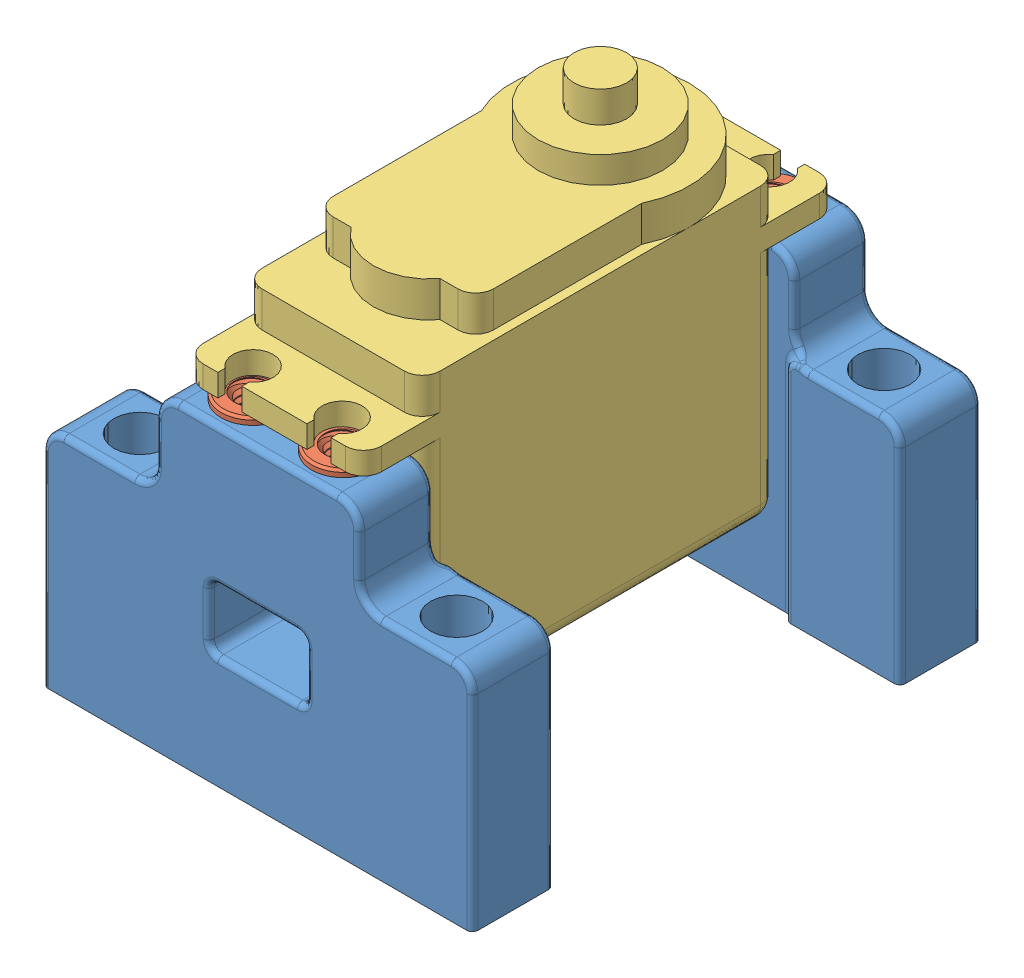
SolidWorks assembly MS-A-0013e-Arm Servo Mount Assembly, configuration Default. Lengths in mm.
Overall size (48.26 52.81 57.28).
11 component instances, 3 part files, 27 mates.
Components (placement in the parent):
- MS-P-0056-Shoulder Servo Mount-6: MS-P-0056-Shoulder Servo Mount [Default] at (-47.9263 -13.6934 17.7337) x (-1 0 0) z (0 1 0) size (48.26 9.14 35.05)
- MS-P-0056-Shoulder Servo Mount-7: MS-P-0056-Shoulder Servo Mount [Default] at (-47.9263 -13.6934 -30.2663) x (1 0 0) z (0 1 0) size (48.26 9.14 35.05)
- 97171A170_ HEAT-SET INSERT FOR PLASTIC-1: 97171A170_ HEAT-SET INSERT FOR PLASTIC [97171A170] at (-65.7063 -7.191 17.7337) x (0.915319 0 -0.402729) z (-0.402729 0 -0.915319) size (7.14 9.57 7.14)
- 97171A170_ HEAT-SET INSERT FOR PLASTIC-2: 97171A170_ HEAT-SET INSERT FOR PLASTIC [97171A170] at (-30.1463 -7.191 17.7337) x (1 0 0) z (0 0 -1) size (7.14 9.57 7.14)
- 97171A170_ HEAT-SET INSERT FOR PLASTIC-4: 97171A170_ HEAT-SET INSERT FOR PLASTIC [97171A170] at (-30.1463 -7.191 -30.2663) x (-1 0 0) z (0 0 1) size (7.14 9.57 7.14)
- 97171A170_ HEAT-SET INSERT FOR PLASTIC-6: 97171A170_ HEAT-SET INSERT FOR PLASTIC [97171A170] at (-65.7063 -7.191 -30.2663) x (1 0 0) z (0 0 -1) size (7.14 9.57 7.14)
- 97171A170_ HEAT-SET INSERT FOR PLASTIC-7: 97171A170_ HEAT-SET INSERT FOR PLASTIC [97171A170] at (-42.8463 8.1252 -30.2663) x (0.999861 0 -0.016687) z (0.016687 0 0.999861) size (7.14 9.57 7.14)
- 97171A170_ HEAT-SET INSERT FOR PLASTIC-8: 97171A170_ HEAT-SET INSERT FOR PLASTIC [97171A170] at (-53.0063 8.1252 -30.2663) size (7.14 9.57 7.14)
- 97171A170_ HEAT-SET INSERT FOR PLASTIC-9: 97171A170_ HEAT-SET INSERT FOR PLASTIC [97171A170] at (-42.8463 8.1252 17.7337) size (7.14 9.57 7.14)
- 97171A170_ HEAT-SET INSERT FOR PLASTIC-10: 97171A170_ HEAT-SET INSERT FOR PLASTIC [97171A170] at (-53.0063 8.1252 17.7337) size (7.14 9.57 7.14)
- MS-C-0032-Gripper Shoulder Servo-1: MS-C-0032-Gripper Shoulder Servo [Default] at (-48.0063 17.0406 -6.2663) x (0 0 -1) z (1 0 0) size (53.2 43.5 20)
Mates (geometry in assembly coordinates):
- Concentric18: concentric anti-aligned: circle of MS-P-0048 - Servo Mount Piece-6; circle of 97171A170_ HEAT-SET INSERT FOR PLASTIC-1
- Concentric22: concentric anti-aligned: circle of 11886-2/11886_upper-1; circle of MS-P-0048 - Servo Mount Piece-7
- Coincident23: coincident anti-aligned: plane of MS-P-0048 - Servo Mount Piece-6 through (-65.7063 -15.3444 17.7337) normal (0 -1 0); plane of 97171A170_ HEAT-SET INSERT FOR PLASTIC-1 through (-63.4861 -15.3444 16.7568) normal (0 1 0)
- Concentric23: concentric anti-aligned: circle of MS-P-0048 - Servo Mount Piece-6; circle of 97171A170_ HEAT-SET INSERT FOR PLASTIC-2
- Coincident28: coincident anti-aligned: plane of MS-P-0048 - Servo Mount Piece-6 through (-30.1463 -15.3444 17.7337) normal (0 -1 0); plane of 97171A170_ HEAT-SET INSERT FOR PLASTIC-2 through (-27.7206 -15.3444 17.7337) normal (0 1 0)
- Concentric24: concentric aligned: circle of MS-P-0048 - Servo Mount Piece-7; circle of 97171A170_ HEAT-SET INSERT FOR PLASTIC-4
- Coincident29: coincident anti-aligned: plane of MS-P-0048 - Servo Mount Piece-7 through (-30.1463 -15.3444 -30.2663) normal (0 -1 0); plane of 97171A170_ HEAT-SET INSERT FOR PLASTIC-4 through (-32.572 -15.3444 -30.2663) normal (0 1 0)
- Concentric25: concentric anti-aligned: circle of MS-P-0048 - Servo Mount Piece-7; circle of 97171A170_ HEAT-SET INSERT FOR PLASTIC-6
- Coincident30: coincident anti-aligned: plane of MS-P-0048 - Servo Mount Piece-7 through (-65.7063 -15.3444 -30.2663) normal (0 -1 0); plane of 97171A170_ HEAT-SET INSERT FOR PLASTIC-6 through (-63.2806 -15.3444 -30.2663) normal (0 1 0)
- Coincident38: coincident anti-aligned: line of MS-P-0048 - Servo Mount Piece-7 through (-42.8463 14.2466 -30.2663) axis (0 1 0); line of 97171A170_ HEAT-SET INSERT FOR PLASTIC-7 through (-42.8463 17.8175 -30.2663) axis (0 -1 0)
- Coincident39: coincident anti-aligned: plane of MS-P-0048 - Servo Mount Piece-7 through (-47.9263 16.2786 -30.2663) normal (0 1 0); plane of 97171A170_ HEAT-SET INSERT FOR PLASTIC-7 through (-40.421 16.2786 -30.3068) normal (0 -1 0)
- Coincident40: coincident anti-aligned: line of MS-P-0048 - Servo Mount Piece-7 through (-53.0063 14.2466 -30.2663) axis (0 1 0); line of 97171A170_ HEAT-SET INSERT FOR PLASTIC-8 through (-53.0063 17.8175 -30.2663) axis (0 -1 0)
- Coincident41: coincident anti-aligned: plane of MS-P-0048 - Servo Mount Piece-7 through (-47.9263 16.2786 -30.2663) normal (0 1 0); plane of 97171A170_ HEAT-SET INSERT FOR PLASTIC-8 through (-50.5806 16.2786 -30.2663) normal (0 -1 0)
- Coincident42: coincident anti-aligned: line of MS-P-0048 - Servo Mount Piece-6 through (-42.8463 14.2466 17.7337) axis (0 1 0); line of 97171A170_ HEAT-SET INSERT FOR PLASTIC-9 through (-42.8463 17.8175 17.7337) axis (0 -1 0)
- Coincident43: coincident anti-aligned: plane of MS-P-0048 - Servo Mount Piece-6 through (-47.9263 16.2786 17.7337) normal (0 1 0); plane of 97171A170_ HEAT-SET INSERT FOR PLASTIC-9 through (-40.4206 16.2786 17.7337) normal (0 -1 0)
- Coincident44: coincident anti-aligned: line of MS-P-0048 - Servo Mount Piece-6 through (-53.0063 14.2466 17.7337) axis (0 1 0); line of 97171A170_ HEAT-SET INSERT FOR PLASTIC-10 through (-53.0063 17.8175 17.7337) axis (0 -1 0)
- Coincident46: coincident anti-aligned: plane of 11886-2/11886_upper-1 through (-24.7983 61.0137 -1.8155) normal (0 -1 0); plane of 97171A170_ HEAT-SET INSERT FOR PLASTIC-9 through (-39.2776 17.0406 17.7337) normal (0 1 0)
- Concentric26: concentric aligned: cylinder of 11886-2/11886_upper-1 through (-9.2983 69.7137 -6.4155) axis (0 -1 0) radius 2.25; cylinder of 97171A170_ HEAT-SET INSERT FOR PLASTIC-9 through (-42.8463 8.1252 17.7337) axis (0 -1 0) radius 3.5687
- Coincident47: coincident anti-aligned: plane of 11886-2/11886_upper-1 through (-24.7983 61.0137 -1.8155) normal (0 -1 0); plane of 97171A170_ HEAT-SET INSERT FOR PLASTIC-7 through (-39.2781 17.0406 -30.3259) normal (0 1 0)
- Parallel2: parallel aligned: plane of 11886-2/11886_upper-1 through (-3.7983 69.7137 39.6845) normal (0 0 1); plane of MS-P-0048 - Servo Mount Piece-7 through (-72.0563 -18.7734 -25.6943) normal (0 0 1)
- Parallel3: parallel aligned: plane of 11886-2/11886_upper-1 through (-3.7983 69.7137 -1.8155) normal (0 0 -1); plane of MS-P-0048 - Servo Mount Piece-6 through (-23.7963 -18.7734 13.1617) normal (0 0 -1)
- Coincident57: coincident anti-aligned: plane of MS-P-0048 - Servo Mount Piece-6 through (-47.9263 16.2786 17.7337) normal (0 1 0); plane of 97171A170_ HEAT-SET INSERT FOR PLASTIC-10 through (-50.5806 16.2786 17.7337) normal (0 -1 0)
- Coincident58: coincident aligned: plane of MS-P-0048 - Servo Mount Piece-6 through (-72.0563 -18.7734 22.3057) normal (-1 0 0); plane of MS-P-0048 - Servo Mount Piece-7 through (-72.0563 -18.7734 -34.8383) normal (-1 0 0)
- Coincident59: coincident aligned: plane of MS-P-0048 - Servo Mount Piece-6 through (-47.9263 -18.7734 17.7337) normal (0 -1 0); plane of MS-P-0048 - Servo Mount Piece-7 through (-47.9263 -18.7734 -30.2663) normal (0 -1 0)
- Concentric27: concentric aligned: circle of 97171A170_ HEAT-SET INSERT FOR PLASTIC-8; circle of MS-C-0029 - D956-WP Servo-1
- Concentric28: concentric anti-aligned: circle of 97171A170_ HEAT-SET INSERT FOR PLASTIC-10; circle of MS-C-0029 - D956-WP Servo-1
- Coincident60: coincident anti-aligned: plane of 97171A170_ HEAT-SET INSERT FOR PLASTIC-8 through (-49.4376 17.0406 -30.2663) normal (0 1 0); plane of MS-C-0029 - D956-WP Servo-1 through (-48.0063 17.0406 -6.2663) normal (0 -1 0)
